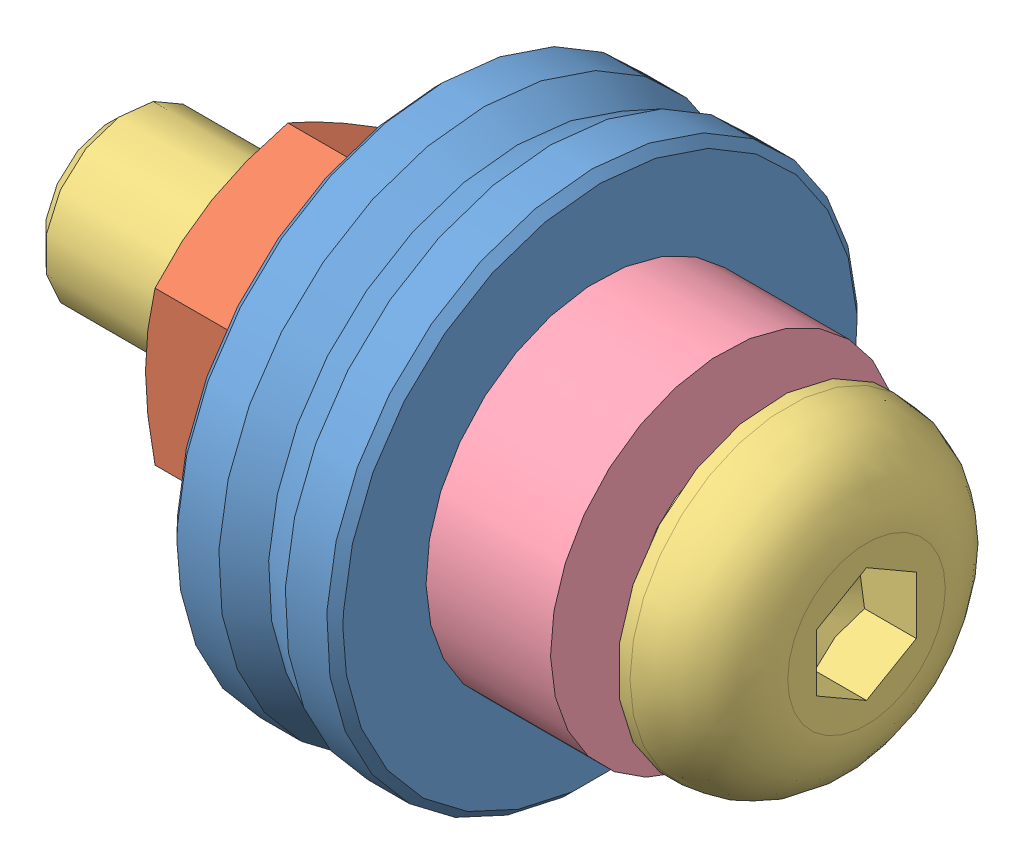
SolidWorks assembly PULLEY ASSEMBLY, configuration Default. Lengths in mm.
Overall size (22.75 16 16).
4 component instances, 4 part files, 9 mates.
Components (placement in the parent):
- 625vv-1: 625vv [Default] at origin size (5 16 16)
- M5 NUT-1: M5 NUT [Default] at (-7.2 0 0) x (1 0 0) z (0 0.866025 0.5) size (4.7 9.24 8)
- M5X20-1: M5X20 [Default] at (7.7689 0 0) x (-1 0 0) z (0 0.5 -0.866025) size (22.75 9.5 9.5)
- PULLEY SPACER-1: PULLEY SPACER [Default] at (2.5 0 0) x (0 -0.5 -0.866025) z (1 0 0) size (10.5 10.5 3.75)
Mates (geometry in assembly coordinates):
- Concentric1: concentric anti-aligned: cylinder of M5X20-1 through (-3.0311 0 0) axis (-1 0 0) radius 2.5; cylinder of PULLEY SPACER-1 through (2.5 0 0) axis (1 0 0) radius 5.25
- Concentric2: concentric aligned: cone of 625vv-1 through (0.5 0 0) axis (-1 0 0); cylinder of M5X20-1 through (-3.0311 0 0) axis (-1 0 0) radius 2.5
- Distance1: distance = 5.2689 mm anti-aligned: plane of M5X20-1 through (7.7689 3.1393 1.8125) normal (-1 0 0); plane of 625vv-1 through (2.5 5.25 0) normal (1 0 0)
- Distance2: distance = 1.5189 mm anti-aligned: plane of M5X20-1 through (7.7689 3.1393 1.8125) normal (-1 0 0); plane of PULLEY SPACER-1 through (6.25 0 0) normal (1 0 0)
- Concentric3: concentric anti-aligned: cylinder of M5 NUT-1 through (-15.5929 0 0) axis (1 0 0) radius 2.067; cylinder of M5X20-1 through (-3.0311 0 0) axis (-1 0 0) radius 2.5
- Coincident3: coincident anti-aligned: plane of 625vv-1 through (-2.5 5.25 0) normal (-1 0 0); plane of M5 NUT-1 through (-2.5 0 0) normal (1 0 0)
- Parallel1: parallel anti-aligned: plane of M5 NUT-1 through (-7.2 2.3094 -4) normal (0 0 -1); plane of assembly through (0 0 0) normal (0 0 1)
- Symmetric1: symmetric anti-aligned: plane of M5X20-1; plane of assembly through (0 0 0) normal (0 0 1); plane of PULLEY SPACER-1
- Parallel2: parallel aligned: plane of M5 NUT-1 through (-7.2 4.6188 0) normal (0 0.866025 -0.5); plane of M5X20-1 through (10.5189 -0.866 1.5) normal (0 0.866025 -0.5)
